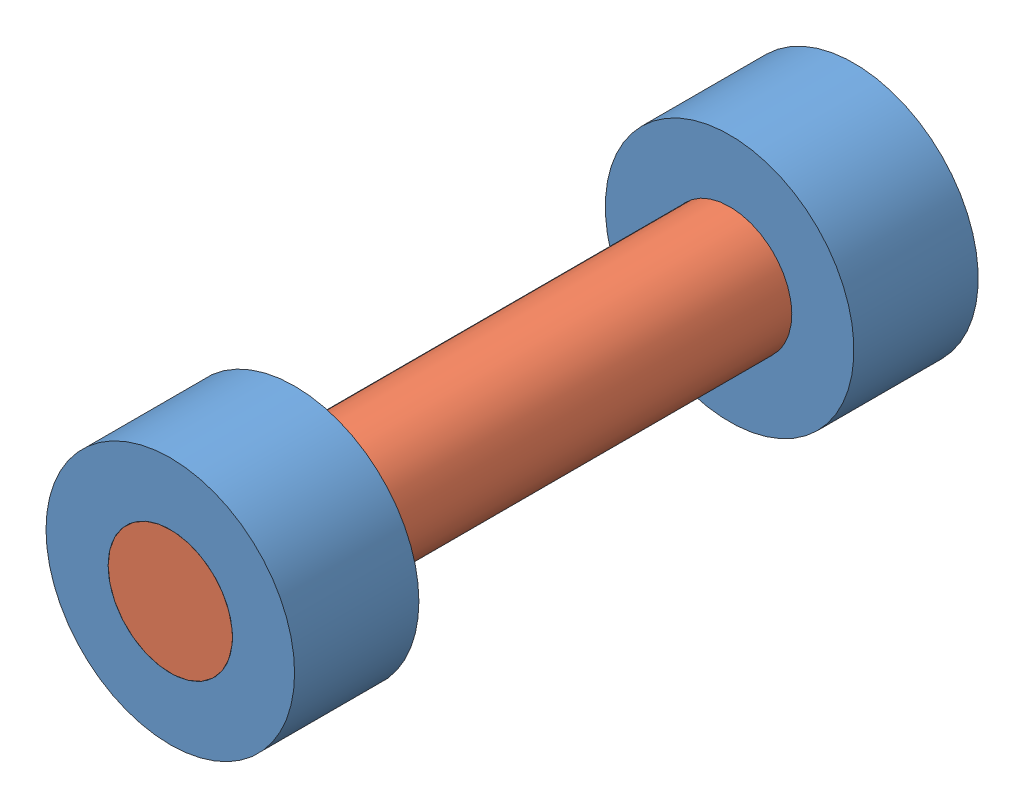
SolidWorks assembly Train Axel-Washer, configuration Default. Lengths in mm.
Overall size (13.47 13.47 34.92).
3 component instances, 2 part files, 4 mates.
Components (placement in the parent):
- Axel Washer-1: Axel Washer [Default] at (3.006 8.2673 6.3746) size (12.7 12.7 6.35)
- Train Axel-1: Train Axel [Default] at (3.006 8.2673 -22.2004) size (6.35 6.35 34.92)
- Axel Washer-2: Axel Washer [Default] at (3.006 8.2673 -22.2004) x (0.99803 -0.06274 0) z (0 0 1) size (12.7 12.7 6.35)
Mates (geometry in assembly coordinates):
- Coincident1: coincident aligned: plane of Axel Washer-1 through (3.006 8.2673 12.7246) normal (0 0 1); plane of Train Axel-1 through (3.006 8.2673 12.7246) normal (0 0 1)
- Concentric1: concentric aligned: cylinder of Axel Washer-1 through (3.006 8.2673 12.7246) axis (0 0 -1) radius 3.175; cylinder of Train Axel-1 through (3.006 8.2673 12.7246) axis (0 0 -1) radius 3.175
- Concentric2: concentric aligned: circle of Train Axel-1; circle of Axel Washer-2
- Coincident2: coincident aligned: plane of Train Axel-1 through (3.006 8.2673 -22.2004) normal (0 0 -1); plane of Axel Washer-2 through (3.006 8.2673 -22.2004) normal (0 0 -1)
